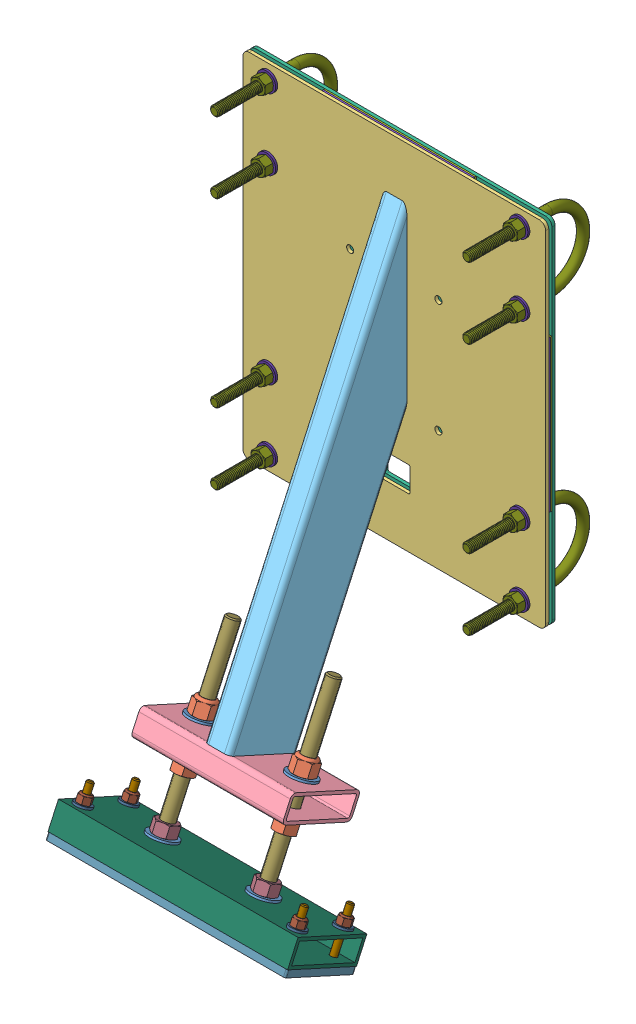
SolidWorks assembly GE-20068, configuration Default. Lengths in mm.
Overall size (304.8 1118.4 748.02).
57 component instances, 17 part files, 22 mates.
Components (placement in the parent):
- washer_flat_.5-1: washer_flat_.5 [98023A029] at (-50.8 -306.4216 164.4532) x (0.438198 0.372759 0.817945) z (0.898879 -0.181718 -0.398743) size (26.99 2.03 26.99)
- nylock_.50_13-6: nylock_.50_13 [nylock_.5_13] at (-50.8 -321.994 171.55) x (-0.125554 -0.411412 -0.902761) z (0.992087 -0.052066 -0.114249) size (19.05 15.73 22)
- washer_flat_.5-2: washer_flat_.5 [98023A029] at (-50.8 -281.4595 153.0774) x (0.438198 0.372759 0.817945) z (0.898879 -0.181718 -0.398743) size (26.99 2.03 26.99)
- nylock_.50_13-3: nylock_.50_13 [nylock_.5_13] at (-50.8 -281.4595 153.0774) x (-0.99916 0.016999 0.0373) z (-0.040991 -0.414345 -0.909196) size (19.05 15.73 22)
- GE-20089-1: GE-20089 [20090] at (0 0 9.525) x (-1 0 0) z (0 0 -1) size (304.8 500.02 258.94)
  - GE-20081-1: GE-20081 [Default<As Machined>] at origin size (304.8 355.6 3.17)
  - GE-20086-1: GE-20086 [Default<As Machined>] at (0 -294.8651 -149.6616) x (1 0 0) z (0 -0.414693 0.909961) size (152.4 25.4 76.2)
  - GE-20083-1: GE-20083 [Default<As Machined>] at (0 -86.848 -54.8627) x (0 -0.909961 -0.414693) z (-1 0 0) size (431.8 76.2 25.4)
- GE-20066-1: GE-20066 [Default] at origin size (304.8 355.6 340.49)
  - GE-20087-1: GE-20087 [Default<As Machined>] at origin size (304.8 355.6 3.17)
  - Loop_1_6-2: Loop_1_6 [Default] at (-76.2 177.8 4.7625) x (1 0 0) z (0 1 0) size (152.4 1.59 25.4)
  - Loop_1_6-3: Loop_1_6 [Default] at (-152.4 -76.2 4.7625) x (0 1 0) z (-1 0 0) size (152.4 1.59 25.4)
  - Loop_1_6-4: Loop_1_6 [Default] at (152.4 76.2 4.7625) x (0 -1 0) z (1 0 0) size (152.4 1.59 25.4)
  - Loop_1_6-5: Loop_1_6 [Default] at (-76.2 -152.4 4.7625) x (1 0 0) z (0 1 0) size (152.4 1.59 25.4)
  - Hook_1_6-1: Hook_1_6 [Default] at (-152.4 -76.2 6.35) x (0 1 0) z (-1 0 0) size (152.4 1.59 25.4)
  - Hook_1_6-2: Hook_1_6 [Default] at (-76.2 177.8 6.35) x (1 0 0) z (0 1 0) size (152.4 1.59 25.4)
  - Hook_1_6-3: Hook_1_6 [Default] at (127 -76.2 6.35) x (0 1 0) z (-1 0 0) size (152.4 1.59 25.4)
  - Hook_1_6-4: Hook_1_6 [Default] at (-76.2 -152.4 6.35) x (1 0 0) z (0 1 0) size (152.4 1.59 25.4)
- GE-20072-1: GE-20072 [Default] at (0 -390.9286 202.9653) x (-1 0 0) z (0 -0.414693 -0.909961) size (241.3 754.83 76.2)
  - flat_phil_.25_20_2-1: flat_phil_.25_20_2 [flat_phil_.25_20_2] at (-107.95 -2.0255 -25.4) x (0.990416 0 0.138116) z (0 -1 0) size (12.12 12.12 50.8)
  - washer_flat_.25-1: washer_flat_.25 [98023A029] at (-107.95 27.432 -25.4) x (1 0 0) z (0 0 -1) size (15.88 2.03 15.88)
  - nylock_.25_20-2: nylock_.25_20 [Default] at (-107.95 27.432 -25.4) x (0.027835 0 -0.999613) z (0.999613 0 0.027835) size (11.11 7.94 12.83)
  - washer_flat_.5-4: washer_flat_.5 [98023A029] at (-50.8 25.4 0) x (0.930219 0 -0.367005) z (0.367005 0 0.930219) size (26.99 2.03 26.99)
  - washer_flat_.5-5: washer_flat_.5 [98023A029] at (-50.8 20.32 0) x (0.99985 0 0.017307) z (-0.017307 0 0.99985) size (26.99 2.03 26.99)
  - hex_.5_13_7-3: hex_.5_13_7 [92865A732] at (-50.8 104.8544 0) x (0 1 0) z (-0.367005 0 0.930219) size (186.53 22 19.05)
  - hexnut_.5_13-3: hexnut_.5_13 [95462A033] at (-50.8 32.9882 0) x (0.989243 0 0.146284) z (0 -1 0) size (19.05 22 11.11)
  - GE-20085-1: GE-20085 [Default] x (1 0 0) z (0 -1 0) size (241.3 76.2 6.35)
  - GE-20084-2: GE-20084 [Default<As Machined>] at (0 12.7 0) size (241.3 25.4 76.2)
  - washer_flat_.25-2: washer_flat_.25 [98023A029] at (107.95 27.432 25.4) x (1 0 0) z (0 0 -1) size (15.88 2.03 15.88)
  - washer_flat_.25-3: washer_flat_.25 [98023A029] at (-107.95 27.432 25.4) x (1 0 0) z (0 0 -1) size (15.88 2.03 15.88)
  - washer_flat_.25-5: washer_flat_.25 [98023A029] at (107.95 27.432 -25.4) x (1 0 0) z (0 0 -1) size (15.88 2.03 15.88)
  - nylock_.25_20-3: nylock_.25_20 [Default] at (107.95 27.432 25.4) x (0.027835 0 -0.999613) z (0.999613 0 0.027835) size (11.11 7.94 12.83)
  - nylock_.25_20-4: nylock_.25_20 [Default] at (-107.95 27.432 25.4) x (0.027835 0 -0.999613) z (0.999613 0 0.027835) size (11.11 7.94 12.83)
  - nylock_.25_20-6: nylock_.25_20 [Default] at (107.95 27.432 -25.4) x (0.027835 0 -0.999613) z (0.999613 0 0.027835) size (11.11 7.94 12.83)
  - flat_phil_.25_20_2-2: flat_phil_.25_20_2 [flat_phil_.25_20_2] at (107.95 -2.0255 25.4) x (0.990416 0 0.138116) z (0 -1 0) size (12.12 12.12 50.8)
  - flat_phil_.25_20_2-3: flat_phil_.25_20_2 [flat_phil_.25_20_2] at (-107.95 -2.0255 25.4) x (0.990416 0 0.138116) z (0 -1 0) size (12.12 12.12 50.8)
  - flat_phil_.25_20_2-5: flat_phil_.25_20_2 [flat_phil_.25_20_2] at (107.95 -2.0255 -25.4) x (0.990416 0 0.138116) z (0 -1 0) size (12.12 12.12 50.8)
  - washer_flat_.5-6: washer_flat_.5 [98023A029] at (50.8 20.32 0) x (0.99985 0 0.017307) z (-0.017307 0 0.99985) size (26.99 2.03 26.99)
  - washer_flat_.5-9: washer_flat_.5 [98023A029] at (50.8 25.4 0) x (0.930219 0 -0.367005) z (0.367005 0 0.930219) size (26.99 2.03 26.99)
  - hexnut_.5_13-7: hexnut_.5_13 [95462A033] at (50.8 32.9882 0) x (0.989243 0 0.146284) z (0 -1 0) size (19.05 22 11.11)
  - hex_.5_13_7-4: hex_.5_13_7 [92865A732] at (50.8 104.8544 0) x (0 1 0) z (-0.367005 0 0.930219) size (186.53 22 19.05)
- nylock_.50_13-7: nylock_.50_13 [nylock_.5_13] at (50.8 -321.994 171.55) x (-0.125554 -0.411412 -0.902761) z (0.992087 -0.052066 -0.114249) size (19.05 15.73 22)
- washer_flat_.5-3: washer_flat_.5 [98023A029] at (50.8 -306.4216 164.4532) x (0.438198 0.372759 0.817945) z (0.898879 -0.181718 -0.398743) size (26.99 2.03 26.99)
- washer_flat_.5-4: washer_flat_.5 [98023A029] at (50.8 -281.4595 153.0774) x (0.438198 0.372759 0.817945) z (0.898879 -0.181718 -0.398743) size (26.99 2.03 26.99)
- nylock_.50_13-5: nylock_.50_13 [nylock_.5_13] at (50.8 -281.4595 153.0774) x (-0.99916 0.016999 0.0373) z (-0.040991 -0.414345 -0.909196) size (19.05 15.73 22)
- GE-20069-1: GE-20069 [8875T859] at (127 127 -17.8779) x (0 1 0) z (1 0 0) size (87.94 123.06 14.29)
- GE-20069-2: GE-20069 [8875T859] at (-127 127 -17.8779) x (0 1 0) z (1 0 0) size (87.94 123.06 14.29)
- GE-20069-3: GE-20069 [8875T859] at (127 -127 -17.8779) x (0 1 0) z (1 0 0) size (87.94 123.06 14.29)
- GE-20069-4: GE-20069 [8875T859] at (-127 -127 -17.8779) x (0 1 0) z (1 0 0) size (87.94 123.06 14.29)
- washer_flat_.375-1: washer_flat_.375 [98023A029] at (127 162.7188 9.525) x (-0.949746 0.313023 0) z (0.313023 0.949746 0) size (19.05 2.03 19.05)
- washer_flat_.375-2: washer_flat_.375 [98023A029] at (-127 162.7188 9.525) x (-0.949746 0.313023 0) z (0.313023 0.949746 0) size (19.05 2.03 19.05)
- washer_flat_.375-3: washer_flat_.375 [98023A029] at (-127 91.2812 9.525) x (-0.949746 0.313023 0) z (0.313023 0.949746 0) size (19.05 2.03 19.05)
- washer_flat_.375-4: washer_flat_.375 [98023A029] at (-127 -91.2812 9.525) x (-0.949746 0.313023 0) z (0.313023 0.949746 0) size (19.05 2.03 19.05)
- washer_flat_.375-5: washer_flat_.375 [98023A029] at (-127 -162.7188 9.525) x (-0.949746 0.313023 0) z (0.313023 0.949746 0) size (19.05 2.03 19.05)
- washer_flat_.375-6: washer_flat_.375 [98023A029] at (127 -162.7188 9.525) x (-0.949746 0.313023 0) z (0.313023 0.949746 0) size (19.05 2.03 19.05)
- washer_flat_.375-7: washer_flat_.375 [98023A029] at (127 -91.2812 9.525) x (-0.949746 0.313023 0) z (0.313023 0.949746 0) size (19.05 2.03 19.05)
- washer_flat_.375-8: washer_flat_.375 [98023A029] at (127 91.2812 9.525) x (-0.949746 0.313023 0) z (0.313023 0.949746 0) size (19.05 2.03 19.05)
Mates (geometry in assembly coordinates):
- Coincident1: coincident anti-aligned: plane of GE-20089-1/GE-20081-1 through (0 0 6.35) normal (0 0 -1); plane of GE-20066-1/Hook_1_6-3 through (127 -76.2 6.35) normal (0 0 1)
- Coincident2: coincident aligned: plane of GE-20089-1/GE-20081-1 through (152.4 177.8 6.35) normal (0 1 0); plane of GE-20066-1/GE-20087-1 through (-152.4 177.8 3.175) normal (0 1 0)
- Coincident3: coincident aligned: plane of GE-20089-1/GE-20081-1 through (-152.4 177.8 6.35) normal (-1 0 0); plane of GE-20066-1/GE-20087-1 through (-152.4 177.8 3.175) normal (-1 0 0)
- Concentric1: concentric aligned: cylinder of GE-20089-1/GE-20086-1 through (-50.8 -283.3086 153.92) axis (0 0.909961 -0.414693) radius 6.7462; cylinder of GE-20072-1/hex_.5_13_7-4 through (-50.8 -372.4382 194.5387) axis (0 0.909961 -0.414693) radius 6.35
- Concentric2: concentric aligned: cylinder of GE-20089-1/GE-20086-1 through (50.8 -283.3086 153.92) axis (0 0.909961 -0.414693) radius 6.7462; cylinder of GE-20072-1/hex_.5_13_7-3 through (50.8 -372.4382 194.5387) axis (0 0.909961 -0.414693) radius 6.35
- Concentric31: concentric aligned: cylinder of GE-20089-1/GE-20086-1 through (-50.8 -283.3086 153.92) axis (0 0.909961 -0.414693) radius 6.7462; cylinder of washer_flat_.5-1 through (-50.8 -308.2706 165.2959) axis (0 0.909961 -0.414693) radius 13.4938
- Coincident41: coincident anti-aligned: plane of GE-20089-1/GE-20086-1 through (76.2 -292.5968 194.7891) normal (0 -0.909961 0.414693); plane of washer_flat_.5-1 through (-50.8 -306.4216 164.4532) normal (0 0.909961 -0.414693)
- Concentric41: concentric aligned: cylinder of washer_flat_.5-1 through (-50.8 -306.4216 164.4532) axis (0 -0.909961 0.414693) radius 6.7469; circle of nylock_.50_13-3
- Concentric51: concentric aligned: cylinder of GE-20089-1/GE-20086-1 through (-50.8 -283.3086 153.92) axis (0 0.909961 -0.414693) radius 6.7462; cylinder of washer_flat_.5-2 through (-50.8 -283.3086 153.92) axis (0 0.909961 -0.414693) radius 13.4938
- Coincident61: coincident anti-aligned: plane of GE-20089-1/GE-20086-1 through (76.2 -297.1334 123.5842) normal (0 0.909961 -0.414693); plane of washer_flat_.5-2 through (-50.8 -283.3086 153.92) normal (0 -0.909961 0.414693)
- Concentric61: concentric anti-aligned: cylinder of washer_flat_.5-2 through (-50.8 -283.3086 153.92) axis (0 0.909961 -0.414693) radius 13.4938; cylinder of nylock_.50_13-6 through (-50.8 -310.4885 166.3066) axis (0 -0.909961 0.414693) radius 5.7213
- Coincident71: coincident anti-aligned: plane of washer_flat_.5-2 through (-50.8 -281.4595 153.0774) normal (0 0.909961 -0.414693); plane of nylock_.50_13-3 through (-50.3492 -276.9024 163.0772) normal (0 -0.909961 0.414693)
- Concentric7: concentric anti-aligned: cylinder of GE-20089-1/GE-20081-1 through (127 91.2812 6.35) axis (0 0 -1) radius 6.7469; cylinder of GE-20069-1 through (127 91.2812 0.3784) axis (0 0 1) radius 4.7625
- Concentric8: concentric anti-aligned: cylinder of GE-20089-1/GE-20081-1 through (127 162.7188 6.35) axis (0 0 -1) radius 6.7469; cylinder of GE-20069-1 through (127 162.7188 -17.8779) axis (0 0 1) radius 4.7625
- Distance1: distance = 67.4688 mm anti-aligned: plane of GE-20063-1/GE-20089-1/GE-20086-1 through (76.2 -292.5968 194.7891) normal (0 -0.909961 0.414693); plane of GE-20072-1/GE-20084-2 through (120.65 -352.0157 227.1016) normal (0 0.909961 -0.414693)
- Concentric62: concentric anti-aligned: cylinder of GE-20089-1/GE-20081-1 through (127 162.7188 6.35) axis (0 0 -1) radius 6.7469; cylinder of washer_flat_.375-1 through (127 162.7188 9.525) axis (0 0 1) radius 5.1562
- Coincident73: coincident anti-aligned: plane of GE-20089-1/GE-20081-1 through (0 0 9.525) normal (0 0 1); plane of washer_flat_.375-1 through (127 162.7188 9.525) normal (0 0 -1)
- Coincident74: coincident anti-aligned: plane of GE-20069-1 through (134.1438 166.8432 11.557) normal (0 0 -1); plane of washer_flat_.375-1 through (127 162.7188 11.557) normal (0 0 1)
- Coincident75: coincident anti-aligned: plane of GE-20066-1/GE-20087-1 through (0 0 0) normal (0 0 -1)
- Coincident76: coincident aligned: plane of GE-20089-1 through (0 0 9.525) normal (0 1 0)
- Coincident77: coincident anti-aligned: plane of GE-20089-1 through (0 0 9.525) normal (-1 0 0)
- Coincident78: coincident aligned: plane of washer_flat_.5-1 through (-50.8 -308.2706 165.2959) normal (0 -0.909961 0.414693); circle of nylock_.50_13-6
